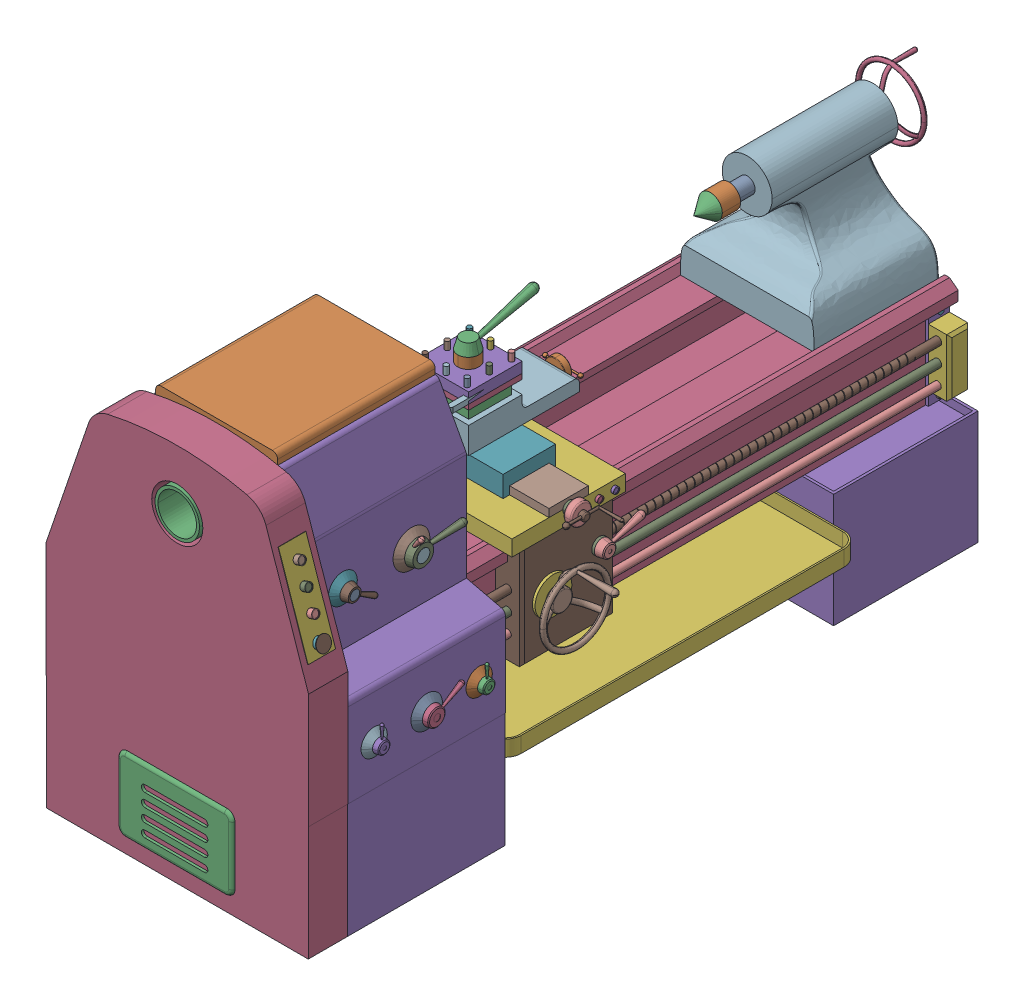
SolidWorks assembly CY6140____.STEP, configuration 默认. Lengths in mm.
Overall size (1148.43 1459.87 2827.09).
4 component instances, 3 part files, 0 mates.
Components (placement in the parent):
- CY6140________.STEP-1: CY6140________.STEP [默认] at (-628.9751 138.378 1403.5468) size (1042.03 1459.87 2827.09)
- CY6140________-0.STEP-1: CY6140________-0.STEP [默认] at (-628.9751 138.378 1815.3981) size (987.43 871.86 582.56)
- r23fwerwfe.STEP-1: r23fwerwfe.STEP [默认] at (-25.4859 413.562 486.7925) x (-1 0 0) z (0 0 -1) size (20 20 150)
- r23fwerwfe.STEP-2: r23fwerwfe.STEP [默认] at (-232.4642 393.562 486.7925) x (1 0 0) z (0 0 -1) size (20 20 150)
